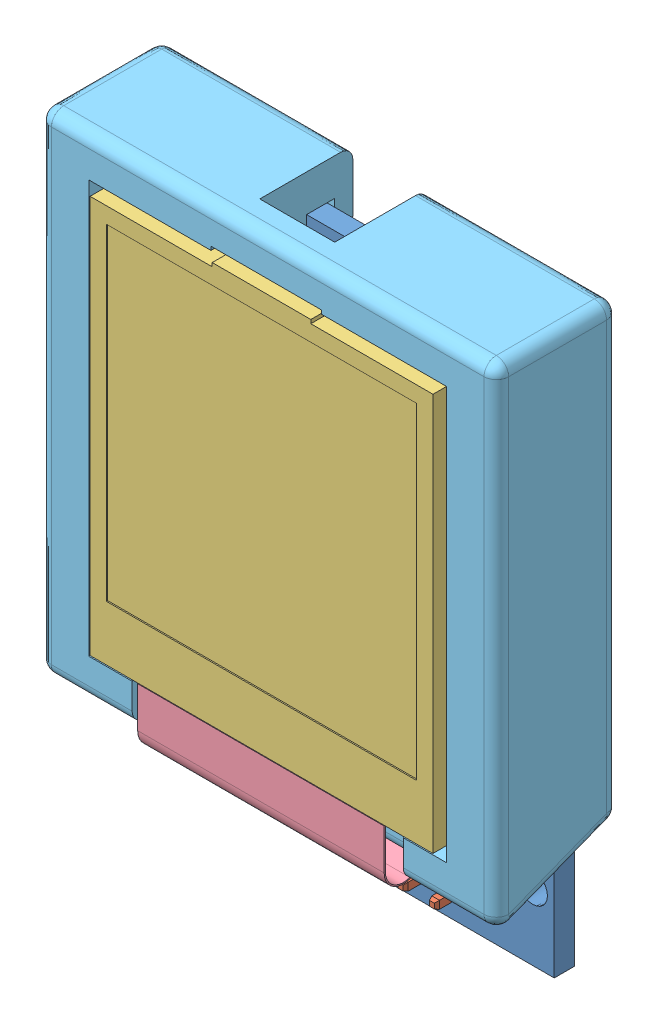
SolidWorks assembly Screen Assembly v3, configuration Default. Lengths in mm.
Overall size (37.1 46.9 15.7).
6 component instances, 6 part files, 17 mates.
Components (placement in the parent):
- Screen v3 PCB-1: Screen v3 PCB [33.5mm wide] at origin size (33.5 43.6 1.65)
- Straight Header - 1x8-1: Straight Header - 1x8 [Default] at (40.64 -19.55 0) size (20.12 2.54 10.71)
- TFT panel-1: TFT panel [Default] at (0 6.75 7.15) size (27.82 32.57 1.5)
- Part3^Screen Assembly v3-1: Part3^Screen Assembly v3 [Default] x (0 0 -1) z (1 0 0) size (7.1 4.85 20) (virtual)
- Screen Bracket-1: Screen Bracket [Default] at origin size (37.1 39.78 9.95)
- PCB backlight-1: PCB backlight [Default] at (0 5.48 3.25) size (27.94 30.48 2.05)
Mates (geometry in assembly coordinates):
- Coincident5: coincident: plane of assembly through (0 0 0) normal (1 0 0); plane of TFT panel-1 through (0 6.75 7.15) normal (1 0 0); plane of assembly
- Distance2: distance = 5.5 mm: plane of ? through (0 0 1.65) normal (0 0 1); plane of TFT panel-1 through (0 6.75 7.15) normal (0 0 -1)
- Distance3: distance = 0.5 mm: plane of ? through (16.75 21.8 1.65) normal (0 1 0); plane of TFT panel-1 through (4 21.3 8.65) normal (0 1 0)
- InPlace1: in place: plane of Part3^Screen Assembly v3-1 through (0 0 0) normal (1 0 0); moOrthogonalPlaneRef_w of Part3^Screen Assembly v3-1 through (0 0 0) normal (0 1 0); plane of Part3^Screen Assembly v3-1 through (0 0 0) normal (0 0 -1); unknown of Part3^Screen Assembly v3-1
- Coincident8: coincident: plane of assembly; plane of Part3^Screen Assembly v3-1; plane of assembly
- Coincident9: coincident: plane of assembly; plane of Part3^Screen Assembly v3-1 through (0 0 0) normal (0 1 0); moOrthogonalPlaneRef_w of assembly
- Coincident10: coincident: plane of assembly; plane of Part3^Screen Assembly v3-1 through (0 0 0) normal (0 0 -1); moOrthogonalPlaneRef_w of assembly
- InPlace2: in place: plane of ? through (0 0 0) normal (0 0 1); plane of ? through (0 0 0) normal (0 1 0); plane of ? through (0 0 0) normal (1 0 0); unknown of ?
- Coincident11: coincident: plane of assembly; plane of Screen Bracket-1; plane of assembly
- Coincident12: coincident: plane of ? through (0 0 0) normal (0 1 0)
- Coincident13: coincident: plane of ? through (0 0 0) normal (1 0 0)
- Width5: width: plane of ? through (-9.215 -19.225 3.05) normal (1 0 0); plane of ? through (9.215 -19.225 3.05) normal (-1 0 0); plane of Straight Header - 1x8-1 through (9.2012 -19.8675 3.714) normal (1 0 0); plane of Straight Header - 1x8-1 through (-9.2012 -19.2325 3.714) normal (-1 0 0)
- Coincident12: coincident: plane of ? through (0 0 0) normal (0 0 -1); plane of Straight Header - 1x8-1 through (40.64 -19.55 0) normal (0 0 1)
- Width6: width: plane of Straight Header - 1x8-1 through (-8.5789 -19.2325 3.714) normal (0 1 0); plane of Straight Header - 1x8-1 through (-9.2012 -19.8675 3.714) normal (0 -1 0); plane of ? through (-9.215 -19.875 3.05) normal (0 1 0); plane of ? through (-9.215 -19.225 3.05) normal (0 -1 0)
- Coincident13: coincident: plane of ? through (0 0 1.65) normal (0 0 1); plane of PCB backlight-1 through (-12.446 20.72 1.65) normal (0 0 -1)
- Coincident14: coincident: plane of assembly through (0 0 0) normal (1 0 0); plane of PCB backlight-1 through (0 5.48 3.25) normal (1 0 0); plane of assembly
- Width7: width: plane of assembly; plane of assembly; plane of assembly; plane of assembly; plane of TFT panel-1 through (-12.585 -6.5 8.65) normal (0 1 0); plane of TFT panel-1 through (-12.585 20 8.65) normal (0 -1 0); plane of PCB backlight-1 through (10.86 14.97 3.25) normal (0 1 0); plane of PCB backlight-1 through (10.86 -1.47 3.25) normal (0 -1 0)
